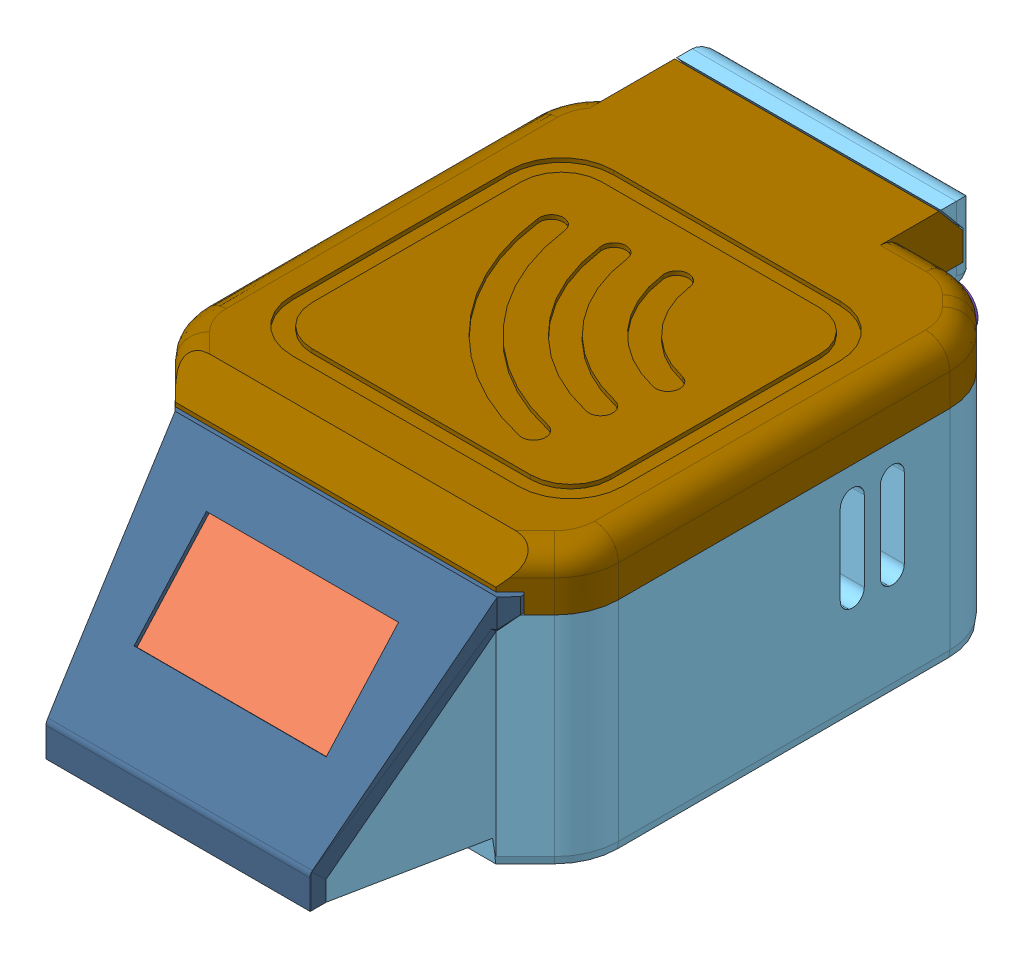
SolidWorks assembly lukija, configuration Default. Lengths in mm.
Overall size (52 34 91.31).
13 component instances, 11 part files, 22 mates.
Components (placement in the parent):
- lukijan elektroniikka-1: lukijan elektroniikka [Default] at (29.2081 50.2061 45.4792) size (43.35 29.16 85.47)
  - PCB-1: PCB [Default] at (16.6694 25.0848 42.0529) size (41.9 14.65 64.92)
  - OLED-1: OLED [Default] at (35.6484 22.4939 85.6685) x (1 0 0) z (0 -0.743145 0.669131) size (27.5 5.1 27.8)
  - NFC-1: NFC [Default] at (38.3863 38.6848 56.2691) size (42.9 6.4 40.5)
- paino 40x40mm-1: paino 40x40mm [Default] at (57.4251 61.2909 91.2932) size (39.5 3.65 39.5)
- paino 40x40mm-2: paino 40x40mm [Default] at (57.4251 64.9409 91.2932) size (39.5 3.65 39.5)
- 3d_kotelon pohja-1: 3d_kotelon pohja [Default] at (56.9251 63.2909 92.2932) size (52 34 87.31)
- 3d_painolukko-1: 3d_painolukko [Default] at (57.4251 67.5909 91.2932) size (17 3 17)
- M3x6 button head-1: M3x6 button head [Default] at (57.4251 63.0909 91.2932) size (5.48 7.8 5.48)
- USB-liitin-1: USB-liitin [Default] at (64.8803 82.5109 66.2932) size (10.5 5.5 13.45)
- 3d_kotelon kansi-1: 3d_kotelon kansi [Default] at (56.9251 87.2909 91.2932) size (52 7 67.35)
- 3d_näytön suoja-1: 3d_näytön suoja [Default] at (56.9725 76.6423 129.3408) x (1 0 0) z (0 -0.743145 0.669131) size (42.75 6.96 37.55)
- M3x25-2: M3x25 [Default] at (73.9251 93.2909 65.5432) x (-0.837169 0 -0.546944) z (-0.546944 0 0.837169) size (5.6 28 5.6)
Mates (geometry in assembly coordinates):
- Coincident1: coincident anti-aligned: plane of paino 40x40mm-1 through (57.4251 64.9409 91.2932) normal (0 1 0); plane of paino 40x40mm-2 through (57.4251 64.9409 91.2932) normal (0 -1 0)
- Coincident2: coincident aligned: plane of paino 40x40mm-1 through (77.1751 64.9409 71.5432) normal (1 0 0); plane of paino 40x40mm-2 through (77.1751 68.5909 71.5432) normal (1 0 0)
- Coincident3: coincident aligned: plane of paino 40x40mm-1 through (37.6751 64.9409 111.0432) normal (0 0 1); plane of paino 40x40mm-2 through (37.6751 68.5909 111.0432) normal (0 0 1)
- Coincident4: coincident anti-aligned: plane of paino 40x40mm-1 through (57.4251 61.2909 91.2932) normal (0 -1 0); circle of 3d_kotelon pohja-1
- Distance1: distance = 0.25 mm anti-aligned: plane of 3d_kotelon pohja-1 through (40.4251 64.2909 111.2932) normal (0 0 -1); plane of paino 40x40mm-1 through (37.6751 64.9409 111.0432) normal (0 0 1)
- Distance2: distance = 0.25 mm anti-aligned: plane of 3d_kotelon pohja-1 through (37.4251 64.2909 74.2932) normal (1 0 0); plane of paino 40x40mm-2 through (37.6751 68.5909 71.5432) normal (-1 0 0)
- Coincident7: coincident anti-aligned: plane of lukijan elektroniikka-1/PCB-1 through (45.8775 75.2909 87.5322) normal (0 -1 0); plane of 3d_kotelon pohja-1 through (56.9251 75.2909 92.2932) normal (0 1 0)
- Distance3: distance = 1 mm anti-aligned: plane of lukijan elektroniikka-1/PCB-1 through (36.8751 76.8909 114.0432) normal (0 0 1); plane of 3d_kotelon pohja-1 through (73.4251 72.2909 115.0432) normal (0 0 -1)
- Distance4: distance = 0.45 mm anti-aligned: plane of 3d_kotelon pohja-1 through (36.4251 72.2909 110.0432) normal (1 0 0); plane of lukijan elektroniikka-1/PCB-1 through (36.8751 76.8909 68.0432) normal (-1 0 0)
- Concentric1: concentric aligned: cylinder of paino 40x40mm-2 through (57.4251 68.5909 91.2932) axis (0 -1 0) radius 6.95; cylinder of 3d_painolukko-1 through (57.4251 -932.4091 91.2932) axis (0 -1 0) radius 5
- Coincident10: coincident anti-aligned: plane of paino 40x40mm-2 through (57.4251 68.5909 91.2932) normal (0 1 0); plane of 3d_painolukko-1 through (50.9251 68.5909 91.2932) normal (0 -1 0)
- Coincident11: coincident aligned: circle of 3d_painolukko-1; plane of M3x6 button head-1 through (55.9751 69.0909 91.2932) normal (0 -1 0)
- Concentric2: concentric anti-aligned: cylinder of paino 40x40mm-1 through (57.4251 64.9409 91.2932) axis (0 -1 0) radius 6.95; cylinder of M3x6 button head-1 through (57.4251 70.8909 91.2932) axis (0 1 0) radius 1.45
- Coincident12: coincident anti-aligned: plane of lukijan elektroniikka-1/PCB-1 through (60.9751 83.6909 67.7432) normal (0 0 -1); plane of USB-liitin-1 through (62.3853 82.5109 67.7432) normal (0 0 1)
- Distance5: distance = 0.25 mm aligned: plane of USB-liitin-1 through (62.3853 83.4409 67.7432) normal (0 1 0); plane of lukijan elektroniikka-1/PCB-1 through (45.8775 83.6909 87.5322) normal (0 1 0)
- Coincident14: coincident aligned: plane of 3d_kotelon pohja-1 through (82.9251 87.2909 115.2932) normal (1 0 0); plane of 3d_kotelon kansi-1 through (82.9251 94.2909 67.2932) normal (1 0 0)
- Coincident15: coincident aligned: plane of 3d_kotelon pohja-1 through (76.9251 87.2909 61.2932) normal (0 0 -1); plane of 3d_kotelon kansi-1 through (36.9251 94.2909 61.2932) normal (0 0 -1)
- Coincident16: coincident anti-aligned: plane of 3d_kotelon pohja-1 through (56.9251 87.2909 92.2932) normal (0 1 0); plane of 3d_kotelon kansi-1 through (56.9251 87.2909 91.2932) normal (0 -1 0)
- Coincident17: coincident anti-aligned: plane of 3d_kotelon pohja-1 through (30.9251 90.4164 116.9385) normal (0 0.669131 0.743145); plane of 3d_näytön suoja-1 through (56.9725 76.6423 129.3408) normal (0 -0.669131 -0.743145)
- Coincident18: coincident aligned: line of 3d_kotelon pohja-1 through (40.4751 65.8667 139.0432) axis (1 0 0); line of 3d_näytön suoja-1 through (40.4725 65.8667 139.0432) axis (1 0 0)
- Coincident20: coincident anti-aligned: circle of 3d_kotelon pohja-1; plane of M3x25-2 through (75.139 68.2909 66.3362) normal (0 1 0)
- Concentric4: concentric aligned: circle of 3d_kotelon pohja-1; cylinder of M3x25-2 through (73.9251 65.2909 65.5432) axis (0 -1 0) radius 1.45
